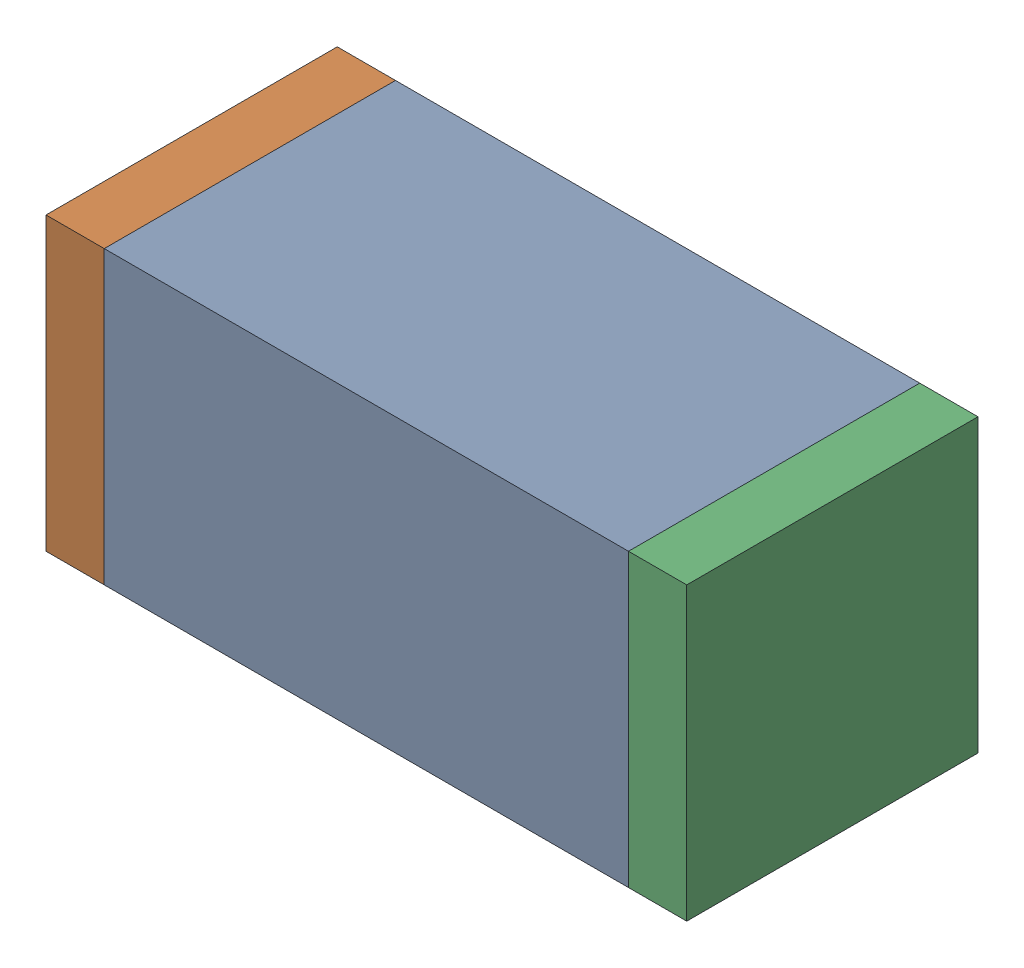
SolidWorks assembly C62, configuration Default. Lengths in mm.
Overall size (1.1 0.5 0.5).
6 component instances, 2 part files, 0 mates.
Components (placement in the parent):
- 836749680-1: 836749680 [Default] at (113.1 52.75 0) size (0.9 0.5 0.5)
  - Extruded_4-1: Extruded_4 [Default] at origin size (0.9 0.5 0.5)
- 810156080-1: 810156080 [Default] at (112.6 52.75 0) size (0.1 0.5 0.5)
  - Extruded_5-1: Extruded_5 [Default] at origin size (0.1 0.5 0.5)
- 810156080-2: 810156080 [Default] at (113.6 52.75 0) size (0.1 0.5 0.5)
  - Extruded_5-1: Extruded_5 [Default] at origin size (0.1 0.5 0.5)
